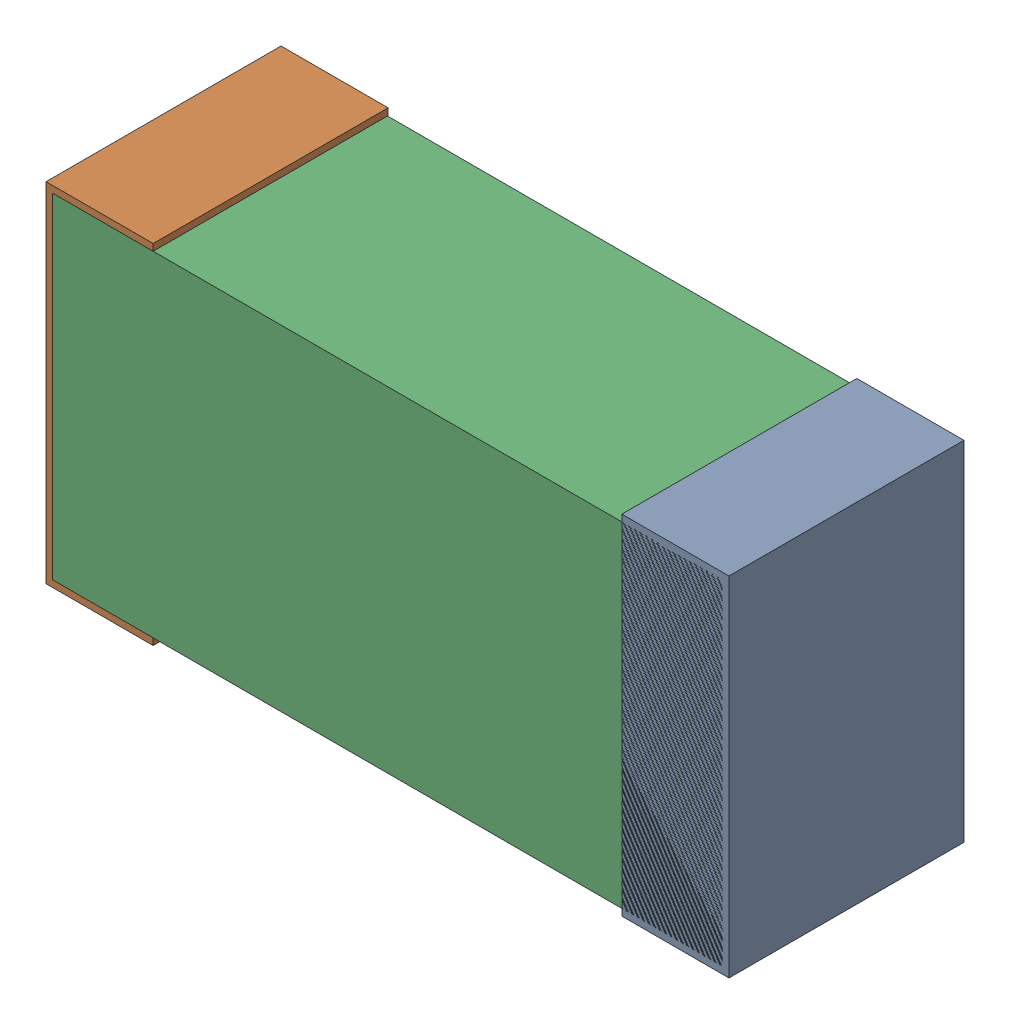
SolidWorks assembly C17, configuration Default. Lengths in mm.
Overall size (1.02 0.52 0.35).
6 component instances, 2 part files, 0 mates.
Components (placement in the parent):
- 870940480-1: 870940480 [Default] at (57.7824 32.2304 -1.9516) size (0.16 0.52 0.35)
  - Extruded-1: Extruded [Default] at origin size (0.16 0.52 0.35)
- 870940480-2: 870940480 [Default] at (56.9224 32.2304 -1.9516) size (0.16 0.52 0.35)
  - Extruded-1: Extruded [Default] at origin size (0.16 0.52 0.35)
- 870940640-1: 870940640 [Default] at (57.3524 32.2304 -1.9506) size (1 0.5 0.35)
  - Extruded_2-1: Extruded_2 [Default] at origin size (1 0.5 0.35)
